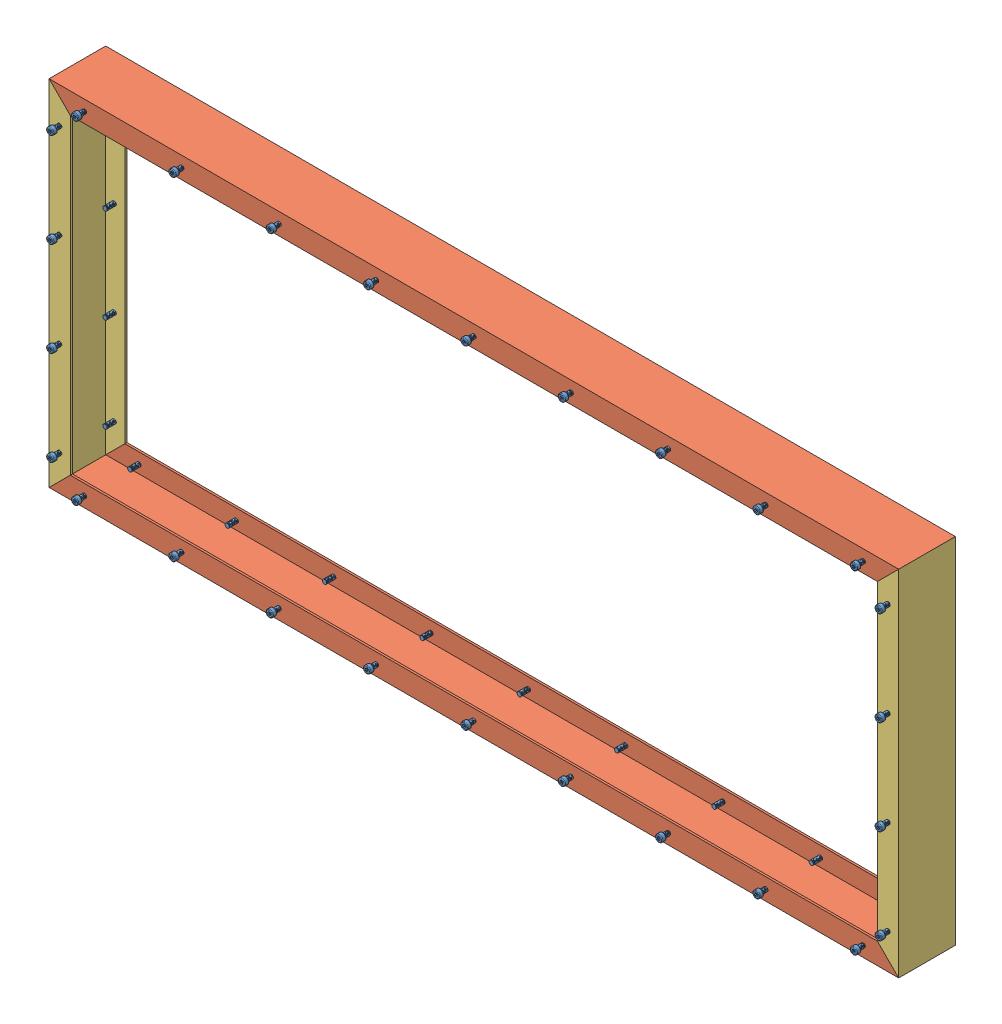
SolidWorks assembly Perfiles, configuration Predeterminado. Lengths in mm.
Overall size (600 250 52.02).
56 component instances, 3 part files, 15 mates.
Components (placement in the parent):
- Tornillo M3x10_CC-1: Tornillo M3x10_CC [Predeterminado] at (-386.1185 381.1648 527.6101) size (5 5 13)
- Tornillo M3x10_CC-2: Tornillo M3x10_CC [Predeterminado] at (-403.6185 363.6648 527.6101) size (5 5 13)
- Tornillo M3x10_CC-3: Tornillo M3x10_CC [Predeterminado] at (-403.6185 363.6648 501.5901) x (1 0 0) z (0 0 -1) size (5 5 13)
- Tornillo M3x10_CC-4: Tornillo M3x10_CC [Predeterminado] at (-386.1185 381.1648 501.5901) x (1 0 0) z (0 0 -1) size (5 5 13)
- Tornillo M3x10_CC-5: Tornillo M3x10_CC [Predeterminado] at (-386.1185 146.1648 501.5901) x (1 0 0) z (0 0 -1) size (5 5 13)
- Tornillo M3x10_CC-6: Tornillo M3x10_CC [Predeterminado] at (-317.3685 381.1648 501.5901) x (1 0 0) z (0 0 -1) size (5 5 13)
- Tornillo M3x10_CC-7: Tornillo M3x10_CC [Predeterminado] at (-317.3685 146.1648 501.5901) x (1 0 0) z (0 0 -1) size (5 5 13)
- Tornillo M3x10_CC-8: Tornillo M3x10_CC [Predeterminado] at (-248.6185 381.1648 501.5901) x (1 0 0) z (0 0 -1) size (5 5 13)
- Tornillo M3x10_CC-9: Tornillo M3x10_CC [Predeterminado] at (-248.6185 146.1648 501.5901) x (1 0 0) z (0 0 -1) size (5 5 13)
- Tornillo M3x10_CC-10: Tornillo M3x10_CC [Predeterminado] at (-179.8685 381.1648 501.5901) x (1 0 0) z (0 0 -1) size (5 5 13)
- Tornillo M3x10_CC-11: Tornillo M3x10_CC [Predeterminado] at (-179.8685 146.1648 501.5901) x (1 0 0) z (0 0 -1) size (5 5 13)
- Tornillo M3x10_CC-12: Tornillo M3x10_CC [Predeterminado] at (-111.1185 381.1648 501.5901) x (1 0 0) z (0 0 -1) size (5 5 13)
- Tornillo M3x10_CC-13: Tornillo M3x10_CC [Predeterminado] at (-111.1185 146.1648 501.5901) x (1 0 0) z (0 0 -1) size (5 5 13)
- Tornillo M3x10_CC-14: Tornillo M3x10_CC [Predeterminado] at (-42.3685 381.1648 501.5901) x (1 0 0) z (0 0 -1) size (5 5 13)
- Tornillo M3x10_CC-15: Tornillo M3x10_CC [Predeterminado] at (-42.3685 146.1648 501.5901) x (1 0 0) z (0 0 -1) size (5 5 13)
- Tornillo M3x10_CC-16: Tornillo M3x10_CC [Predeterminado] at (26.3815 381.1648 501.5901) x (1 0 0) z (0 0 -1) size (5 5 13)
- Tornillo M3x10_CC-17: Tornillo M3x10_CC [Predeterminado] at (26.3815 146.1648 501.5901) x (1 0 0) z (0 0 -1) size (5 5 13)
- Tornillo M3x10_CC-18: Tornillo M3x10_CC [Predeterminado] at (95.1315 381.1648 501.5901) x (1 0 0) z (0 0 -1) size (5 5 13)
- Tornillo M3x10_CC-19: Tornillo M3x10_CC [Predeterminado] at (95.1315 146.1648 501.5901) x (1 0 0) z (0 0 -1) size (5 5 13)
- Tornillo M3x10_CC-20: Tornillo M3x10_CC [Predeterminado] at (163.8815 381.1648 501.5901) x (1 0 0) z (0 0 -1) size (5 5 13)
- Tornillo M3x10_CC-21: Tornillo M3x10_CC [Predeterminado] at (163.8815 146.1648 501.5901) x (1 0 0) z (0 0 -1) size (5 5 13)
- Tornillo M3x10_CC-22: Tornillo M3x10_CC [Predeterminado] at (-386.1185 146.1648 527.6101) size (5 5 13)
- Tornillo M3x10_CC-23: Tornillo M3x10_CC [Predeterminado] at (-317.3685 381.1648 527.6101) size (5 5 13)
- Tornillo M3x10_CC-24: Tornillo M3x10_CC [Predeterminado] at (-317.3685 146.1648 527.6101) size (5 5 13)
- Tornillo M3x10_CC-25: Tornillo M3x10_CC [Predeterminado] at (-248.6185 381.1648 527.6101) size (5 5 13)
- Tornillo M3x10_CC-26: Tornillo M3x10_CC [Predeterminado] at (-248.6185 146.1648 527.6101) size (5 5 13)
- Tornillo M3x10_CC-27: Tornillo M3x10_CC [Predeterminado] at (-179.8685 381.1648 527.6101) size (5 5 13)
- Tornillo M3x10_CC-28: Tornillo M3x10_CC [Predeterminado] at (-179.8685 146.1648 527.6101) size (5 5 13)
- Tornillo M3x10_CC-29: Tornillo M3x10_CC [Predeterminado] at (-111.1185 381.1648 527.6101) size (5 5 13)
- Tornillo M3x10_CC-30: Tornillo M3x10_CC [Predeterminado] at (-111.1185 146.1648 527.6101) size (5 5 13)
- Tornillo M3x10_CC-31: Tornillo M3x10_CC [Predeterminado] at (-42.3685 381.1648 527.6101) size (5 5 13)
- Tornillo M3x10_CC-32: Tornillo M3x10_CC [Predeterminado] at (-42.3685 146.1648 527.6101) size (5 5 13)
- Tornillo M3x10_CC-33: Tornillo M3x10_CC [Predeterminado] at (26.3815 381.1648 527.6101) size (5 5 13)
- Tornillo M3x10_CC-34: Tornillo M3x10_CC [Predeterminado] at (26.3815 146.1648 527.6101) size (5 5 13)
- Tornillo M3x10_CC-35: Tornillo M3x10_CC [Predeterminado] at (95.1315 381.1648 527.6101) size (5 5 13)
- Tornillo M3x10_CC-36: Tornillo M3x10_CC [Predeterminado] at (95.1315 146.1648 527.6101) size (5 5 13)
- Tornillo M3x10_CC-37: Tornillo M3x10_CC [Predeterminado] at (163.8815 381.1648 527.6101) size (5 5 13)
- Tornillo M3x10_CC-38: Tornillo M3x10_CC [Predeterminado] at (163.8815 146.1648 527.6101) size (5 5 13)
- Tornillo M3x10_CC-39: Tornillo M3x10_CC [Predeterminado] at (-403.6185 296.9948 501.5901) x (1 0 0) z (0 0 -1) size (5 5 13)
- Tornillo M3x10_CC-40: Tornillo M3x10_CC [Predeterminado] at (-403.6185 230.3248 501.5901) x (1 0 0) z (0 0 -1) size (5 5 13)
- Tornillo M3x10_CC-41: Tornillo M3x10_CC [Predeterminado] at (-403.6185 163.6548 501.5901) x (1 0 0) z (0 0 -1) size (5 5 13)
- Tornillo M3x10_CC-42: Tornillo M3x10_CC [Predeterminado] at (181.3815 363.6648 501.5901) x (1 0 0) z (0 0 -1) size (5 5 13)
- Tornillo M3x10_CC-43: Tornillo M3x10_CC [Predeterminado] at (181.3815 296.9948 501.5901) x (1 0 0) z (0 0 -1) size (5 5 13)
- Tornillo M3x10_CC-44: Tornillo M3x10_CC [Predeterminado] at (181.3815 230.3248 501.5901) x (1 0 0) z (0 0 -1) size (5 5 13)
- Tornillo M3x10_CC-45: Tornillo M3x10_CC [Predeterminado] at (181.3815 163.6548 501.5901) x (1 0 0) z (0 0 -1) size (5 5 13)
- Tornillo M3x10_CC-46: Tornillo M3x10_CC [Predeterminado] at (-403.6185 296.9948 527.6101) size (5 5 13)
- Tornillo M3x10_CC-47: Tornillo M3x10_CC [Predeterminado] at (-403.6185 230.3248 527.6101) size (5 5 13)
- Tornillo M3x10_CC-48: Tornillo M3x10_CC [Predeterminado] at (-403.6185 163.6548 527.6101) size (5 5 13)
- Tornillo M3x10_CC-49: Tornillo M3x10_CC [Predeterminado] at (181.3815 363.6648 527.6101) size (5 5 13)
- Tornillo M3x10_CC-50: Tornillo M3x10_CC [Predeterminado] at (181.3815 296.9948 527.6101) size (5 5 13)
- Tornillo M3x10_CC-51: Tornillo M3x10_CC [Predeterminado] at (181.3815 230.3248 527.6101) size (5 5 13)
- Tornillo M3x10_CC-52: Tornillo M3x10_CC [Predeterminado] at (181.3815 163.6548 527.6101) size (5 5 13)
- Perfil_Largo_alum-1: Perfil_Largo_alum [Predeterminado] at (-411.1185 138.6648 513.6001) size (600 15 40)
- Perfil_Corto_alum-1: Perfil_Corto_alum [Predeterminado] at (188.8815 138.6648 513.6001) x (0 1 0) z (0 0 1) size (250 15 40)
- Perfil_Corto_alum-2: Perfil_Corto_alum [Predeterminado] at (-411.1185 388.6648 513.6001) x (0 -1 0) z (0 0 1) size (250 15 40)
- Perfil_Largo_alum-2: Perfil_Largo_alum [Predeterminado] at (188.8815 388.6648 513.6001) x (-1 0 0) z (0 0 1) size (600 15 40)
Mates (geometry in assembly coordinates):
- Coincidente8: coincident aligned: plane of Tornillo M3x10_CC-1 through (-386.1185 381.1648 537.6101) normal (0 0 -1); plane of Tornillo M3x10_CC-2 through (-403.6185 363.6648 537.6101) normal (0 0 -1)
- Coincidente11: coincident aligned: plane of Tornillo M3x10_CC-3 through (-403.6185 363.6648 488.5901) normal (0 0 -1); plane of Tornillo M3x10_CC-4 through (-386.1185 381.1648 488.5901) normal (0 0 -1)
- Coincidente12: coincident aligned: plane of Perfil_Corto_alum-2 through (-396.1185 138.6648 533.6001) normal (0 0 1); plane of Perfil_Largo_alum-2 through (-411.1185 373.6648 533.6001) normal (0 0 1)
- Coincidente13: coincident aligned: plane of Perfil_Largo_alum-1 through (188.8815 153.6648 533.6001) normal (0 0 1); plane of Perfil_Corto_alum-2 through (-396.1185 138.6648 533.6001) normal (0 0 1)
- Coincidente14: coincident aligned: plane of Perfil_Largo_alum-1 through (188.8815 153.6648 533.6001) normal (0 0 1); plane of Perfil_Corto_alum-1 through (173.8815 388.6648 533.6001) normal (0 0 1)
- Coincidente15: coincident aligned: line of Perfil_Largo_alum-1 through (-411.1185 138.6648 533.6001) axis (0 0 -1); line of Perfil_Corto_alum-2 through (-411.1185 138.6648 533.6001) axis (0 0 -1)
- Coincidente16: coincident aligned: line of Perfil_Corto_alum-2 through (-411.1185 388.6648 533.6001) axis (0 0 -1); line of Perfil_Largo_alum-2 through (-411.1185 388.6648 533.6001) axis (0 0 -1)
- Coincidente17: coincident aligned: line of Perfil_Corto_alum-1 through (188.8815 388.6648 533.6001) axis (0 0 -1); line of Perfil_Largo_alum-2 through (188.8815 388.6648 533.6001) axis (0 0 -1)
- Coincidente18: coincident aligned: line of Perfil_Largo_alum-1 through (188.8815 138.6648 533.6001) axis (0 0 -1); line of Perfil_Corto_alum-1 through (188.8815 138.6648 533.6001) axis (0 0 -1)
- Distancia1: distance = 4.01 mm anti-aligned: plane of Perfil_Corto_alum-2 through (-396.1185 138.6648 533.6001) normal (0 0 1); plane of Tornillo M3x10_CC-1 through (-386.1185 381.1648 537.6101) normal (0 0 -1)
- Distancia2: distance = 2.01 mm anti-aligned: plane of Tornillo M3x10_CC-3 through (-403.6185 363.6648 491.5901) normal (0 0 1); plane of Perfil_Largo_alum-1 through (188.8815 138.6648 493.6001) normal (0 0 -1)
- Concéntrica1: concentric aligned: cylinder of Tornillo M3x10_CC-1 through (-386.1185 381.1648 540.6101) axis (0 0 -1) radius 2.5; cylinder of Perfil_Largo_alum-2 through (-386.1185 381.1648 533.6001) axis (0 0 -1) radius 1.25
- Concéntrica2: concentric aligned: cylinder of Tornillo M3x10_CC-2 through (-403.6185 363.6648 540.6101) axis (0 0 -1) radius 2.5; circle of Perfil_Corto_alum-2
- Concéntrica3: concentric anti-aligned: cylinder of Tornillo M3x10_CC-1 through (-386.1185 381.1648 540.6101) axis (0 0 -1) radius 2.5; cylinder of Tornillo M3x10_CC-4 through (-386.1185 381.1648 488.5901) axis (0 0 1) radius 2.5
- Concéntrica4: concentric anti-aligned: cylinder of Tornillo M3x10_CC-2 through (-403.6185 363.6648 540.6101) axis (0 0 -1) radius 2.5; cylinder of Tornillo M3x10_CC-3 through (-403.6185 363.6648 488.5901) axis (0 0 1) radius 2.5
